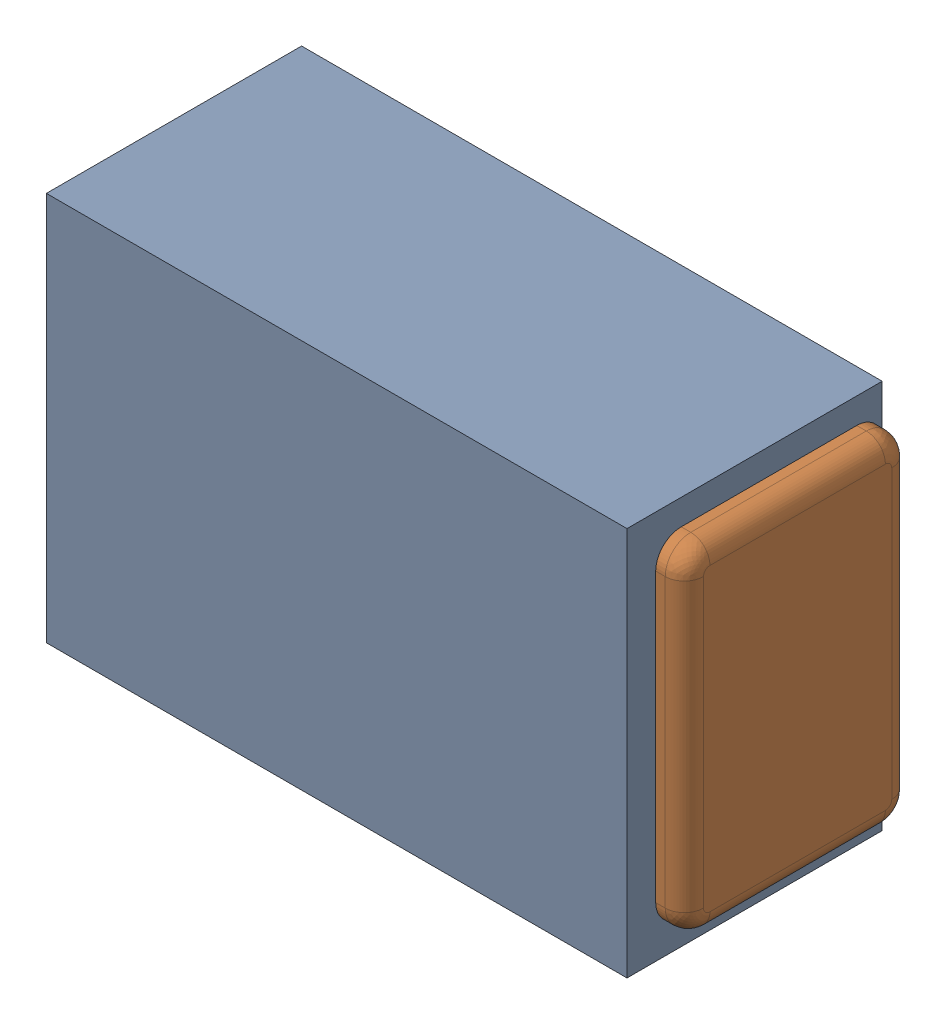
SolidWorks assembly C11, configuration Default. Lengths in mm.
Overall size (1 0.61 0.4).
3 component instances, 2 part files, 0 mates.
Components (placement in the parent):
- 1088880352-1: 1088880352 [Default] at (5.25 38.65 0) size (0.91 0.61 0.4)
  - Extruded-28-1: Extruded-28 [Default] at origin size (0.91 0.61 0.4)
- C0402-1: C0402 [Default] at (5.2499 38.6499 0) x (-1 0 0) z (0 1 0) size (1 0.36 0.54)
